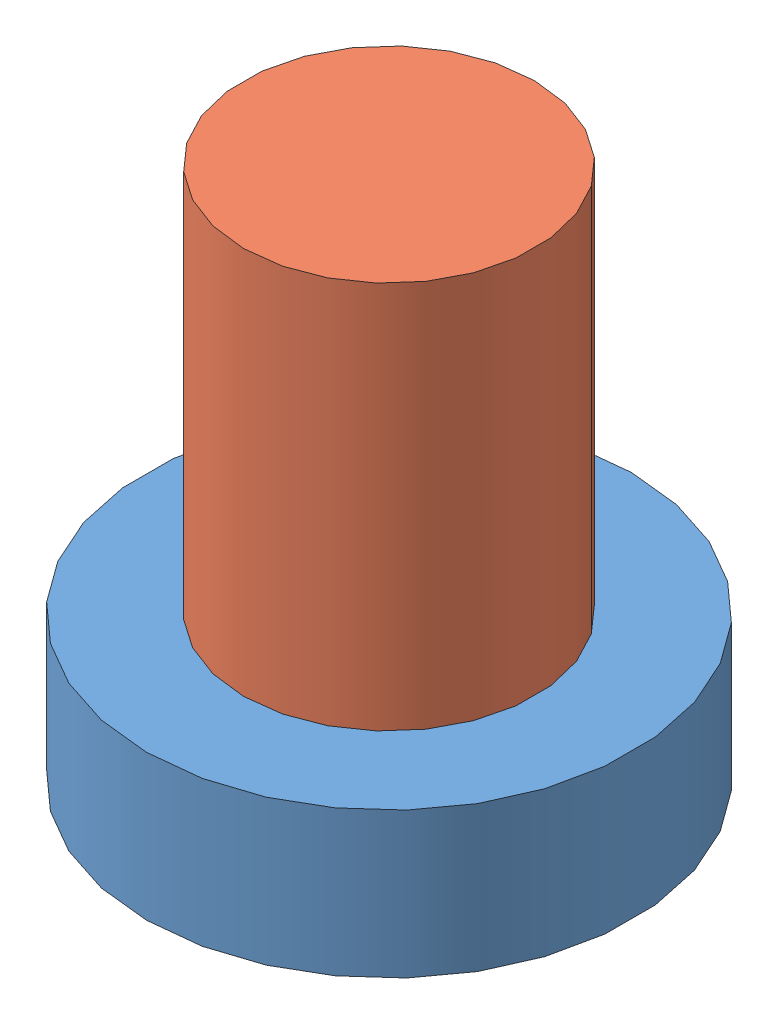
SolidWorks assembly SubAssem, configuration Default. Lengths in mm.
Overall size (100 110 100).
2 component instances, 2 part files, 6 mates.
Components (placement in the parent):
- subpart1-1: subpart1 [Default] at origin size (100 30 100)
- subpart2-1: subpart2 [Default] at (0 30 0) size (60 80 60)
Mates (geometry in assembly coordinates):
- 重合1: coincident aligned: plane of subpart1-1 through (38.1199 0 0) normal (0 0 1)
- 重合2: coincident aligned: plane of subpart1-1 through (38.1199 0 0) normal (0 1 0)
- 重合3: coincident aligned: plane of subpart1-1 through (0 0 0) normal (1 0 0)
- 重合4: coincident: plane of subpart1-1 through (0 0 0) normal (0 0 1); plane of subpart2-1 through (0 -14.5551 0) normal (0 0 1)
- 重合5: coincident: plane of subpart1-1 through (0 0 0) normal (1 0 0); plane of subpart2-1 through (0 -14.5551 0) normal (1 0 0)
- 重合6: coincident anti-aligned: plane of subpart1-1 through (0 30 0) normal (0 1 0); plane of subpart2-1 through (0 30 0) normal (0 -1 0)
